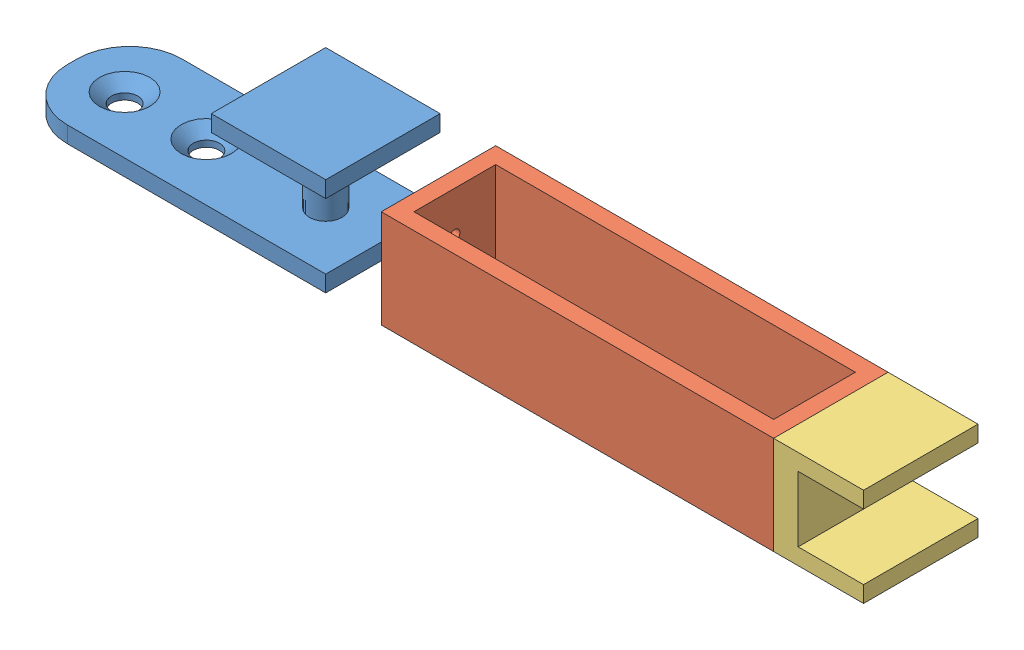
SolidWorks assembly Proto1, configuration Default. Lengths in mm.
Overall size (164.77 19.05 22.23).
3 component instances, 3 part files, 9 mates.
Components (placement in the parent):
- Proto1_anchor-1: Proto1_anchor [Default] at (0 3.175 0) size (60.33 19.05 22.23)
- Proto1_base-1: Proto1_base [Default] at (59.9999 0 0) size (76.2 19.05 22.23)
- Proto1_clip-1: Proto1_clip [Default] at (100.4812 0 0) size (17.46 19.05 22.23)
Mates (geometry in assembly coordinates):
- Coincident4: coincident: plane of Proto1_base-1 through (59.9999 0 0) normal (0 -1 0); plane of assembly through (0 0 0) normal (0 1 0)
- Coincident5: coincident: plane of Proto1_anchor-1 through (0 0 0) normal (0 -1 0); plane of Proto1_base-1 through (59.9999 0 0) normal (0 -1 0)
- Coincident6: coincident: plane of Proto1_base-1 through (59.9999 0 0) normal (0 -1 0); plane of Proto1_clip-1 through (100.4812 0 0) normal (0 -1 0)
- Coincident9: coincident: line of Proto1_anchor-1 through (12.7 0 15.875) axis (0 0 -1); plane of assembly
- Coincident10: coincident: plane of Proto1_anchor-1 through (0 3.175 0) normal (0 0 1); plane of assembly through (0 0 0) normal (0 0 1)
- Coincident11: coincident: plane of Proto1_anchor-1 through (0 3.175 0) normal (1 0 0); plane of assembly through (0 0 0) normal (1 0 0)
- Coincident12: coincident: plane of Proto1_base-1 through (59.9999 0 0) normal (0 0 1); plane of assembly through (0 0 0) normal (0 0 1)
- Coincident13: coincident: plane of Proto1_clip-1 through (100.4812 0 0) normal (0 0 1); plane of assembly through (0 0 0) normal (0 0 1)
- Distance1: distance = 0 mm: plane of Proto1_base-1 through (98.0999 3.175 11.1125) normal (1 0 0); plane of Proto1_clip-1 through (98.0999 3.175 11.1125) normal (-1 0 0)
